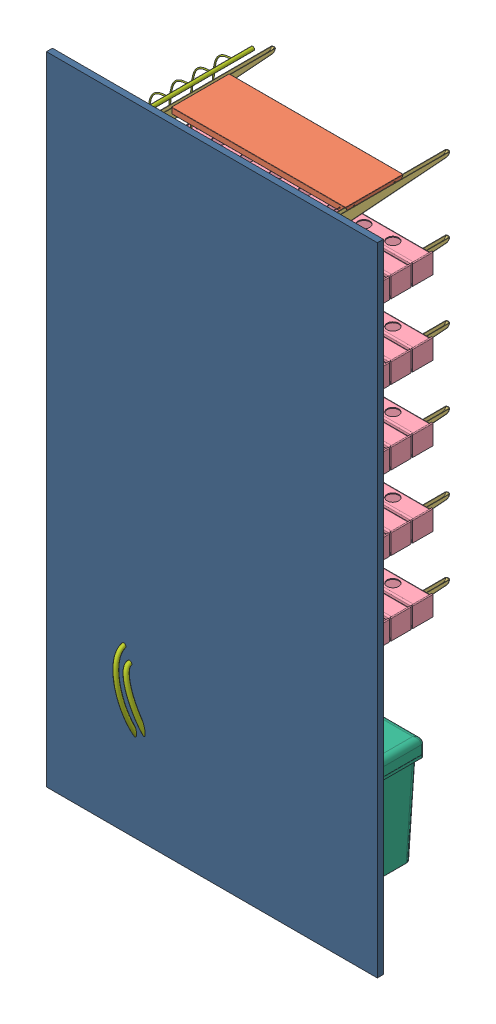
SolidWorks assembly C-W-600, configuration Default. Lengths in mm.
Overall size (1143.31 2200 556.23).
63 component instances, 12 part files, 175 mates.
Components (placement in the parent):
- TSU-W-1: TSU-W [Default] at (314.023 122.1563 -17.0959) size (25 1984 15)
- TSU-W-2: TSU-W [Default] at (-295.977 122.1563 -25) size (25 1984 15)
- TSS-600-1: TSS-600 [Default] at (9.023 818 -235.0528) size (607 37.13 331.17)
- TSUB-1: TSUB [Default] at (314.023 766.5 -17.0959) x (-1 0 0) z (0 0 -1) size (14.07 50.86 484.03)
- TSUB-2: TSUB [Default] at (-295.977 766.5 -25) x (-1 0 0) z (0 0 -1) size (14.07 50.86 484.03)
- TSUB-3: TSUB [Default] at (-295.977 1022.5 -25) x (-1 0 0) z (0 0 -1) size (14.07 50.86 484.03)
- TSUB-4: TSUB [Default] at (314.023 1022.5 -17.0959) x (-1 0 0) z (0 0 -1) size (14.07 50.86 484.03)
- TSS-600-2: TSS-600 [Default] at (9.023 1074 -235.0528) size (607 37.13 331.17)
- TSUB-5: TSUB [Default] at (-295.977 1534.5 -25) x (-1 0 0) z (0 0 -1) size (14.07 50.86 484.03)
- TSUB-6: TSUB [Default] at (314.023 1534.5 -17.0959) x (-1 0 0) z (0 0 -1) size (14.07 50.86 484.03)
- TSS-600-3: TSS-600 [Default] at (9.023 1586 -235.0528) size (607 37.13 331.17)
- TSUB-7: TSUB [Default] at (-295.977 2046.8153 -25) x (-1 0 0) z (0 0 -1) size (14.07 50.86 484.03)
- TSUB-8: TSUB [Default] at (314.023 2046.8153 -17.0959) x (-1 0 0) z (0 0 -1) size (14.07 50.86 484.03)
- TSS-600-4: TSS-600 [Default] at (9.023 2098.3153 -235.0528) size (607 37.13 331.17)
- TSUB-9: TSUB [Default] at (-295.977 1278.5 -25) x (-1 0 0) z (0 0 -1) size (14.07 50.86 484.03)
- TSUB-10: TSUB [Default] at (314.023 1278.5 -17.0959) x (-1 0 0) z (0 0 -1) size (14.07 50.86 484.03)
- TSS-600-5: TSS-600 [Default] at (9.023 1330 -235.0528) size (607 37.13 331.17)
- TSUB-11: TSUB [Default] at (-295.977 1790.5 -25) x (-1 0 0) z (0 0 -1) size (14.07 50.86 484.03)
- TSUB-12: TSUB [Default] at (314.023 1790.5 -17.0959) x (-1 0 0) z (0 0 -1) size (14.07 50.86 484.03)
- TSS-600-6: TSS-600 [Default] at (9.023 1842 -235.0528) size (607 37.13 331.17)
- GB-600-b-1: GB-600-b [Default] at (0 1106.5 -233.7344) size (806 70 70)
- GB-600-p-1: GB-600-p [Default] at (0 1106.5 -233.7344) size (92 218.31 4)
- GB-600-p-2: GB-600-p [Default] at (0 1106.5 -308.7344) size (92 218.31 4)
- GB-600-b-2: GB-600-b [Default] at (0 1106.5 -308.7344) size (806 70 70)
- GB-600-p-3: GB-600-p [Default] at (0 1106.5 -83.7344) size (92 218.31 4)
- GB-600-b-3: GB-600-b [Default] at (0 1106.5 -83.7344) size (806 70 70)
- GB-600-p-4: GB-600-p [Default] at (0 1106.5 -158.7344) size (92 218.31 4)
- GB-600-b-4: GB-600-b [Default] at (0 1106.5 -158.7344) size (806 70 70)
- GB-600-b-5: GB-600-b [Default] at (0 850.5 -83.7344) size (806 70 70)
- GB-600-b-6: GB-600-b [Default] at (0 850.5 -158.7344) size (806 70 70)
- GB-600-b-7: GB-600-b [Default] at (0 850.5 -233.7344) size (806 70 70)
- GB-600-b-8: GB-600-b [Default] at (0 850.5 -308.7344) size (806 70 70)
- GB-600-b-9: GB-600-b [Default] at (0 1618.5 -83.7344) size (806 70 70)
- GB-600-b-10: GB-600-b [Default] at (0 1618.5 -158.7344) size (806 70 70)
- GB-600-b-11: GB-600-b [Default] at (0 1618.5 -233.7344) size (806 70 70)
- GB-600-b-12: GB-600-b [Default] at (0 1618.5 -308.7344) size (806 70 70)
- GB-600-p-5: GB-600-p [Default] at (0 1618.5 -83.7344) size (92 218.31 4)
- GB-600-p-6: GB-600-p [Default] at (0 1618.5 -158.7344) size (92 218.31 4)
- GB-600-p-7: GB-600-p [Default] at (0 1618.5 -233.7344) size (92 218.31 4)
- GB-600-p-8: GB-600-p [Default] at (0 1618.5 -308.7344) size (92 218.31 4)
- GB-600-p-9: GB-600-p [Default] at (0 1362.5 -308.7344) size (92 218.31 4)
- GB-600-p-10: GB-600-p [Default] at (0 1362.5 -233.7344) size (92 218.31 4)
- GB-600-p-11: GB-600-p [Default] at (0 1362.5 -158.7344) size (92 218.31 4)
- GB-600-p-12: GB-600-p [Default] at (0 1362.5 -83.7344) size (92 218.31 4)
- GB-600-b-13: GB-600-b [Default] at (0 1362.5 -308.7344) size (806 70 70)
- GB-600-b-14: GB-600-b [Default] at (0 1362.5 -233.7344) size (806 70 70)
- GB-600-b-15: GB-600-b [Default] at (0 1362.5 -158.7344) size (806 70 70)
- GB-600-b-16: GB-600-b [Default] at (0 1362.5 -83.7344) size (806 70 70)
- GB-600-p-13: GB-600-p [Default] at (0 1874.5 -308.7344) size (92 218.31 4)
- GB-600-p-14: GB-600-p [Default] at (0 1874.5 -233.7344) size (92 218.31 4)
- GB-600-p-15: GB-600-p [Default] at (0 1874.5 -158.7344) size (92 218.31 4)
- GB-600-p-16: GB-600-p [Default] at (0 1874.5 -83.7344) size (92 218.31 4)
- GB-600-b-17: GB-600-b [Default] at (0 1874.5 -83.7344) size (806 70 70)
- GB-600-b-18: GB-600-b [Default] at (0 1874.5 -158.7344) size (806 70 70)
- GB-600-b-19: GB-600-b [Default] at (0 1874.5 -233.7344) size (806 70 70)
- GB-600-b-20: GB-600-b [Default] at (0 1874.5 -308.7344) size (806 70 70)
- WT-1: WT [Default] at (0 320 -217.0959) size (600 370 400)
- Plumbing-1: Plumbing [Default] at (-304.2307 113.1409 -27.6539) size (241.4 2067.5 489.85)
- Wire-1: Wire [Default] at (9.023 2061.1845 -235.0528) x (-1 0 0) z (0 -1 0) size (2 2 1357)
- CCD-1: CCD [Default] at (314.023 122.1563 -17.0959) x (0 0 -1) z (1 0 0) size (82.56 307.09 97.63) (hidden)
- Pump-1: Pump [Default] at (0 5 -217.0959) x (1 0 0) z (0 1 0) size (624.24 196.22 364.08) (hidden)
- power brick-1: power brick [Default] at (321.5508 116.8455 -47.8298) x (0 0 -1) z (1 0 0) size (82.62 120 30)
- Part1^C-W-600-1: Part1^C-W-600 [Default] at (0 0 -217.0959) x (-1 0 0) z (0 -1 0) size (1143.31 20.98 2200) (virtual)
Mates (geometry in assembly coordinates):
- Coincident41: coincident anti-aligned: plane of TSU-W-1 through (307.023 730.1563 -2.0959) normal (1 0 0); plane of TSUB-1 through (307.023 766.5 -17.0959) normal (-1 0 0)
- Coincident42: coincident anti-aligned: plane of TSU-W-1 through (314.023 2106.1563 -17.0959) normal (0 0 -1); plane of TSUB-1 through (321.023 766.5 -17.0959) normal (0 0 1)
- Parallel8: parallel: line of TSU-W-1 through (309 342 -23.5) axis (0 0 -1); plane of TSUB-1 through (299.4677 816.5 -17.0959) normal (0 1 0)
- Coincident44: coincident anti-aligned: plane of TSS-600-1 through (308.523 798 -235.0528) normal (-1 0 0); plane of TSUB-1 through (308.523 766.5 -17.0959) normal (1 0 0)
- Coincident45: coincident anti-aligned: plane of TSS-600-1 through (310.023 816.5 -136.5528) normal (0 -1 0); plane of TSUB-1 through (307.023 816.5 -17.0959) normal (0 1 0)
- Coincident46: coincident anti-aligned: plane of TSU-W-2 through (-302.977 762.1563 -10) normal (1 0 0); plane of TSUB-2 through (-302.977 766.5 -25) normal (-1 0 0)
- Coincident47: coincident anti-aligned: plane of TSU-W-2 through (-295.977 2106.1563 -25) normal (0 0 -1); plane of TSUB-2 through (-302.977 766.5 -25) normal (0 0 1)
- Coincident48: coincident anti-aligned: plane of TSS-600-1 through (310.023 816.5 -136.5528) normal (0 -1 0); plane of TSUB-2 through (-302.977 816.5 -25) normal (0 1 0)
- Coincident49: coincident anti-aligned: plane of TSU-W-1 through (321.023 1018.1563 -2.0959) normal (-1 0 0); plane of TSUB-4 through (321.023 1022.5 -17.0959) normal (1 0 0)
- Coincident50: coincident anti-aligned: plane of TSU-W-1 through (314.023 2106.1563 -17.0959) normal (0 0 -1); plane of TSUB-4 through (321.023 1022.5 -17.0959) normal (0 0 1)
- Coincident51: coincident anti-aligned: plane of TSU-W-2 through (-288.977 1018.1563 -10) normal (-1 0 0); plane of TSUB-3 through (-288.977 1022.5 -25) normal (1 0 0)
- Coincident52: coincident anti-aligned: plane of TSU-W-2 through (-295.977 2106.1563 -25) normal (0 0 -1); plane of TSUB-3 through (-302.977 1022.5 -25) normal (0 0 1)
- Coincident53: coincident anti-aligned: plane of TSUB-4 through (307.023 1072.5 -17.0959) normal (0 1 0); plane of TSS-600-2 through (310.023 1072.5 -136.5528) normal (0 -1 0)
- Coincident54: coincident anti-aligned: plane of TSUB-3 through (-302.977 1072.5 -25) normal (0 1 0); plane of TSS-600-2 through (310.023 1072.5 -136.5528) normal (0 -1 0)
- Coincident55: coincident anti-aligned: plane of TSUB-4 through (308.523 1022.5 -17.0959) normal (1 0 0); plane of TSS-600-2 through (308.523 1054 -235.0528) normal (-1 0 0)
- Coincident56: coincident anti-aligned: plane of TSUB-6 through (308.523 1534.5 -17.0959) normal (1 0 0); plane of TSS-600-3 through (308.523 1566 -235.0528) normal (-1 0 0)
- Coincident57: coincident anti-aligned: plane of TSUB-6 through (307.023 1584.5 -17.0959) normal (0 1 0); plane of TSS-600-3 through (310.023 1584.5 -136.5528) normal (0 -1 0)
- Coincident58: coincident anti-aligned: plane of TSUB-5 through (-302.977 1584.5 -25) normal (0 1 0); plane of TSS-600-3 through (310.023 1584.5 -136.5528) normal (0 -1 0)
- Coincident59: coincident anti-aligned: plane of TSUB-8 through (308.523 2046.8153 -17.0959) normal (1 0 0); plane of TSS-600-4 through (308.523 2078.3153 -235.0528) normal (-1 0 0)
- Coincident60: coincident anti-aligned: plane of TSUB-8 through (307.023 2096.8153 -17.0959) normal (0 1 0); plane of TSS-600-4 through (310.023 2096.8153 -136.5528) normal (0 -1 0)
- Coincident61: coincident anti-aligned: plane of TSUB-7 through (-302.977 2096.8153 -25) normal (0 1 0); plane of TSS-600-4 through (310.023 2096.8153 -136.5528) normal (0 -1 0)
- Coincident62: coincident anti-aligned: plane of TSUB-10 through (308.523 1278.5 -17.0959) normal (1 0 0); plane of TSS-600-5 through (308.523 1310 -235.0528) normal (-1 0 0)
- Coincident63: coincident anti-aligned: plane of TSUB-10 through (307.023 1328.5 -17.0959) normal (0 1 0); plane of TSS-600-5 through (310.023 1328.5 -136.5528) normal (0 -1 0)
- Coincident64: coincident anti-aligned: plane of TSUB-9 through (-302.977 1328.5 -25) normal (0 1 0); plane of TSS-600-5 through (310.023 1328.5 -136.5528) normal (0 -1 0)
- Coincident65: coincident anti-aligned: plane of TSUB-12 through (308.523 1790.5 -17.0959) normal (1 0 0); plane of TSS-600-6 through (308.523 1822 -235.0528) normal (-1 0 0)
- Coincident66: coincident anti-aligned: plane of TSUB-12 through (307.023 1840.5 -17.0959) normal (0 1 0); plane of TSS-600-6 through (310.023 1840.5 -136.5528) normal (0 -1 0)
- Coincident67: coincident anti-aligned: plane of TSUB-11 through (-302.977 1840.5 -25) normal (0 1 0); plane of TSS-600-6 through (310.023 1840.5 -136.5528) normal (0 -1 0)
- Coincident70: coincident anti-aligned: plane of TSU-W-1 through (314.023 2106.1563 -17.0959) normal (0 0 -1); plane of TSUB-10 through (307.023 1278.5 -17.0959) normal (0 0 1)
- Coincident71: coincident anti-aligned: plane of TSU-W-2 through (-295.977 2106.1563 -25) normal (0 0 -1); plane of TSUB-9 through (-302.977 1278.5 -25) normal (0 0 1)
- Coincident72: coincident aligned: plane of TSUB-3 through (-288.977 1022.5 -25) normal (1 0 0); plane of TSUB-9 through (-288.977 1278.5 -25) normal (1 0 0)
- Coincident73: coincident aligned: plane of TSUB-4 through (307.023 1022.5 -17.0959) normal (-1 0 0); plane of TSUB-10 through (307.023 1278.5 -17.0959) normal (-1 0 0)
- Coincident74: coincident anti-aligned: plane of TSU-W-1 through (314.023 2106.1563 -17.0959) normal (0 0 -1); plane of TSUB-6 through (307.023 1534.5 -17.0959) normal (0 0 1)
- Coincident75: coincident anti-aligned: plane of TSU-W-2 through (-295.977 2106.1563 -25) normal (0 0 -1); plane of TSUB-5 through (-302.977 1534.5 -25) normal (0 0 1)
- Coincident76: coincident aligned: plane of TSUB-5 through (-288.977 1534.5 -25) normal (1 0 0); plane of TSUB-9 through (-288.977 1278.5 -25) normal (1 0 0)
- Coincident78: coincident aligned: plane of TSUB-6 through (321.023 1534.5 -17.0959) normal (1 0 0); plane of TSUB-12 through (321.023 1790.5 -17.0959) normal (1 0 0)
- Coincident79: coincident aligned: plane of TSUB-6 through (307.023 1534.5 -17.0959) normal (-1 0 0); plane of TSUB-10 through (307.023 1278.5 -17.0959) normal (-1 0 0)
- Coincident80: coincident anti-aligned: plane of TSU-W-1 through (314.023 2106.1563 -17.0959) normal (0 0 -1); plane of TSUB-12 through (307.023 1790.5 -17.0959) normal (0 0 1)
- Coincident81: coincident anti-aligned: plane of TSU-W-2 through (-302.977 1786.1563 -10) normal (1 0 0); plane of TSUB-11 through (-302.977 1790.5 -25) normal (-1 0 0)
- Coincident82: coincident anti-aligned: plane of TSU-W-2 through (-295.977 2106.1563 -25) normal (0 0 -1); plane of TSUB-11 through (-302.977 1790.5 -25) normal (0 0 1)
- Coincident83: coincident anti-aligned: plane of TSU-W-2 through (-302.977 2042.1563 -10) normal (1 0 0); plane of TSUB-7 through (-302.977 2046.8153 -25) normal (-1 0 0)
- Coincident84: coincident anti-aligned: plane of TSU-W-2 through (-295.977 2106.1563 -25) normal (0 0 -1); plane of TSUB-7 through (-302.977 2046.8153 -25) normal (0 0 1)
- Coincident85: coincident anti-aligned: plane of TSU-W-1 through (307.023 2074.1563 -2.0959) normal (1 0 0); plane of TSUB-8 through (307.023 2046.8153 -17.0959) normal (-1 0 0)
- Coincident86: coincident anti-aligned: plane of TSU-W-1 through (314.023 2106.1563 -17.0959) normal (0 0 -1); plane of TSUB-8 through (307.023 2046.8153 -17.0959) normal (0 0 1)
- Coincident89: coincident: line of TSU-W-1 through (309 2070 -23.5) axis (0 0 -1); plane of TSUB-8 through (334.728 2070 -17.0959) normal (0 1 0)
- Coincident90: coincident aligned: plane of TSS-600-4 through (310.023 2098.3153 -335.0528) normal (0 0 -1); plane of TSS-600-6 through (310.023 1842 -335.0528) normal (0 0 -1)
- Coincident91: coincident aligned: plane of TSS-600-3 through (310.023 1586 -335.0528) normal (0 0 -1); plane of TSS-600-6 through (310.023 1842 -335.0528) normal (0 0 -1)
- Coincident93: coincident aligned: plane of TSS-600-3 through (310.023 1586 -335.0528) normal (0 0 -1); plane of TSS-600-5 through (310.023 1330 -335.0528) normal (0 0 -1)
- Coincident94: coincident aligned: plane of TSS-600-2 through (310.023 1074 -335.0528) normal (0 0 -1); plane of TSS-600-5 through (310.023 1330 -335.0528) normal (0 0 -1)
- Coincident95: coincident aligned: plane of TSS-600-1 through (310.023 818 -335.0528) normal (0 0 -1); plane of TSS-600-2 through (310.023 1074 -335.0528) normal (0 0 -1)
- Coincident153: coincident: line of TSU-F-L-P-1 through (312 1814 -23.5) axis (0 0 -1); plane of TSUB-12 through (333.2603 1814 -25) normal (0 1 0)
- Coincident155: coincident: line of TSU-F-L-P-1 through (312 1558 -23.5) axis (0 0 -1); plane of TSUB-6 through (333.2603 1558 -25) normal (0 1 0)
- Coincident157: coincident: line of TSU-F-L-P-1 through (312 1302 -23.5) axis (0 0 -1); plane of TSUB-10 through (333.2603 1302 -25) normal (0 1 0)
- Coincident159: coincident: line of TSU-F-L-P-1 through (312 1046 -23.5) axis (0 0 -1); plane of TSUB-4 through (333.2603 1046 -25) normal (0 1 0)
- Coincident167: coincident: line of TSU-F-L-P-1 through (312 790 -23.5) axis (0 0 -1); plane of TSUB-1 through (333.2603 790 -25) normal (0 1 0)
- Concentric31: concentric aligned: cylinder of GB-600-b-1 through (-375 1071.5 -233.7344) axis (0 1 0) radius 2; cylinder of GB-600-p-1 through (-375 877 -233.7344) axis (0 1 0) radius 2
- Distance1: distance = 10 mm aligned: plane of GB-600-p-1 through (-375 1087 -233.7344) normal (0 1 0); plane of GB-600-b-1 through (400 1077 -201.2344) normal (0 1 0)
- Parallel10: parallel anti-aligned: plane of TSU-W-1 through (314.023 2106.1563 -17.0959) normal (0 0 -1); plane of GB-600-b-1 through (400 1074 -201.2344) normal (0 0 1)
- Coincident201: coincident aligned: plane of GB-600-b-1 through (0 1106.5 -233.7344) normal (1 0 0)
- Coincident202: coincident anti-aligned: plane of TSS-600-2 through (310.023 1074 -135.0528) normal (0 1 0); plane of GB-600-b-1 through (400 1074 -201.2344) normal (0 -1 0)
- Concentric32: concentric aligned: cylinder of GB-600-p-2 through (-375 877 -308.7344) axis (0 1 0) radius 2; cylinder of GB-600-b-2 through (-375 1071.5 -308.7344) axis (0 1 0) radius 2
- Distance2: distance = 10 mm aligned: plane of GB-600-p-2 through (-375 1087 -308.7344) normal (0 1 0); plane of GB-600-b-2 through (400 1077 -276.2344) normal (0 1 0)
- Concentric33: concentric aligned: cylinder of GB-600-p-3 through (-375 877 -83.7344) axis (0 1 0) radius 2; cylinder of GB-600-b-3 through (-375 1071.5 -83.7344) axis (0 1 0) radius 2
- Distance3: distance = 10 mm aligned: plane of GB-600-p-3 through (-375 1087 -83.7344) normal (0 1 0); plane of GB-600-b-3 through (400 1077 -51.2344) normal (0 1 0)
- Concentric34: concentric aligned: cylinder of GB-600-p-4 through (-375 877 -158.7344) axis (0 1 0) radius 2; cylinder of GB-600-b-4 through (-375 1071.5 -158.7344) axis (0 1 0) radius 2
- Distance4: distance = 10 mm aligned: plane of GB-600-p-4 through (-375 1087 -158.7344) normal (0 1 0); plane of GB-600-b-4 through (400 1077 -126.2344) normal (0 1 0)
- Coincident203: coincident anti-aligned: plane of TSS-600-2 through (310.023 1074 -135.0528) normal (0 1 0); plane of GB-600-b-2 through (400 1074 -276.2344) normal (0 -1 0)
- Coincident204: coincident anti-aligned: plane of TSS-600-2 through (310.023 1074 -135.0528) normal (0 1 0); plane of GB-600-b-4 through (400 1074 -126.2344) normal (0 -1 0)
- Coincident205: coincident anti-aligned: plane of TSS-600-2 through (310.023 1074 -135.0528) normal (0 1 0); plane of GB-600-b-3 through (400 1074 -51.2344) normal (0 -1 0)
- Coincident206: coincident aligned: plane of GB-600-b-1 through (403 1106.5 -233.7344) normal (1 0 0); plane of GB-600-b-4 through (403 1106.5 -158.7344) normal (1 0 0)
- Coincident207: coincident aligned: plane of GB-600-b-3 through (403 1106.5 -83.7344) normal (1 0 0); plane of GB-600-b-4 through (403 1106.5 -158.7344) normal (1 0 0)
- Coincident208: coincident aligned: plane of GB-600-b-1 through (403 1106.5 -233.7344) normal (1 0 0); plane of GB-600-b-2 through (403 1106.5 -308.7344) normal (1 0 0)
- Distance5: distance = 10 mm anti-aligned: plane of GB-600-b-4 through (400 1074 -191.2344) normal (0 0 -1); plane of GB-600-b-1 through (400 1074 -201.2344) normal (0 0 1)
- Distance6: distance = 10 mm anti-aligned: plane of GB-600-b-4 through (400 1074 -126.2344) normal (0 0 1); plane of GB-600-b-3 through (400 1074 -116.2344) normal (0 0 -1)
- Distance7: distance = 10 mm anti-aligned: plane of GB-600-b-1 through (400 1074 -266.2344) normal (0 0 -1); plane of GB-600-b-2 through (400 1074 -276.2344) normal (0 0 1)
- Distance8: distance = 10 mm anti-aligned: plane of GB-600-b-6 through (400 818 -126.2344) normal (0 0 1); plane of GB-600-b-5 through (400 818 -116.2344) normal (0 0 -1)
- Distance9: distance = 10 mm anti-aligned: plane of GB-600-b-6 through (400 818 -191.2344) normal (0 0 -1); plane of GB-600-b-7 through (400 818 -201.2344) normal (0 0 1)
- Coincident212: coincident aligned: plane of GB-600-b-5 through (403 850.5 -83.7344) normal (1 0 0); plane of GB-600-b-6 through (403 850.5 -158.7344) normal (1 0 0)
- Coincident213: coincident aligned: plane of GB-600-b-7 through (403 850.5 -233.7344) normal (1 0 0); plane of GB-600-b-8 through (403 850.5 -308.7344) normal (1 0 0)
- Coincident214: coincident aligned: plane of GB-600-b-6 through (403 850.5 -158.7344) normal (1 0 0); plane of GB-600-b-7 through (403 850.5 -233.7344) normal (1 0 0)
- Distance10: distance = 10 mm anti-aligned: plane of GB-600-b-7 through (400 818 -266.2344) normal (0 0 -1); plane of GB-600-b-8 through (400 818 -276.2344) normal (0 0 1)
- Coincident215: coincident aligned: plane of GB-600-b-7 through (400 818 -201.2344) normal (0 -1 0); plane of GB-600-b-8 through (400 818 -276.2344) normal (0 -1 0)
- Coincident216: coincident aligned: plane of GB-600-b-6 through (400 818 -126.2344) normal (0 -1 0); plane of GB-600-b-7 through (400 818 -201.2344) normal (0 -1 0)
- Coincident217: coincident aligned: plane of GB-600-b-5 through (400 818 -51.2344) normal (0 -1 0); plane of GB-600-b-6 through (400 818 -126.2344) normal (0 -1 0)
- Coincident218: coincident anti-aligned: plane of TSS-600-1 through (310.023 818 -135.0528) normal (0 1 0); plane of GB-600-b-7 through (400 818 -201.2344) normal (0 -1 0)
- Concentric35: concentric aligned: cylinder of GB-600-p-2 through (-375 877 -308.7344) axis (0 1 0) radius 2; cylinder of GB-600-b-8 through (-375 815.499 -308.7344) axis (0 1 0) radius 4
- Concentric36: concentric aligned: cylinder of GB-600-b-9 through (-375 1583.5 -83.7344) axis (0 1 0) radius 2; cylinder of GB-600-p-5 through (-375 1389 -83.7344) axis (0 1 0) radius 2
- Distance11: distance = 10 mm anti-aligned: plane of GB-600-b-10 through (400 1586 -126.2344) normal (0 0 1); plane of GB-600-b-9 through (400 1586 -116.2344) normal (0 0 -1)
- Concentric37: concentric aligned: cylinder of GB-600-b-12 through (-375 1583.5 -308.7344) axis (0 1 0) radius 2; cylinder of GB-600-p-8 through (-375 1389 -308.7344) axis (0 1 0) radius 2
- Concentric38: concentric aligned: cylinder of GB-600-b-11 through (-375 1583.5 -233.7344) axis (0 1 0) radius 2; cylinder of GB-600-p-7 through (-375 1389 -233.7344) axis (0 1 0) radius 2
- Distance12: distance = 10 mm aligned: plane of GB-600-p-7 through (-375 1599 -233.7344) normal (0 1 0); plane of GB-600-b-11 through (400 1589 -201.2344) normal (0 1 0)
- Distance13: distance = 10 mm anti-aligned: plane of GB-600-b-10 through (400 1586 -191.2344) normal (0 0 -1); plane of GB-600-b-11 through (400 1586 -201.2344) normal (0 0 1)
- Concentric39: concentric aligned: cylinder of GB-600-b-10 through (-375 1583.5 -158.7344) axis (0 1 0) radius 2; cylinder of GB-600-p-6 through (-375 1389 -158.7344) axis (0 1 0) radius 2
- Distance14: distance = 10 mm aligned: plane of GB-600-p-8 through (-375 1599 -308.7344) normal (0 1 0); plane of GB-600-b-12 through (400 1589 -276.2344) normal (0 1 0)
- Distance15: distance = 10 mm aligned: plane of GB-600-p-5 through (-375 1599 -83.7344) normal (0 1 0); plane of GB-600-b-9 through (400 1589 -51.2344) normal (0 1 0)
- Distance16: distance = 10 mm aligned: plane of GB-600-p-6 through (-375 1599 -158.7344) normal (0 1 0); plane of GB-600-b-10 through (400 1589 -126.2344) normal (0 1 0)
- Coincident220: coincident aligned: plane of GB-600-b-9 through (403 1618.5 -83.7344) normal (1 0 0); plane of GB-600-b-10 through (403 1618.5 -158.7344) normal (1 0 0)
- Coincident221: coincident aligned: plane of GB-600-b-11 through (403 1618.5 -233.7344) normal (1 0 0); plane of GB-600-b-12 through (403 1618.5 -308.7344) normal (1 0 0)
- Coincident222: coincident aligned: plane of GB-600-b-10 through (403 1618.5 -158.7344) normal (1 0 0); plane of GB-600-b-11 through (403 1618.5 -233.7344) normal (1 0 0)
- Distance17: distance = 10 mm anti-aligned: plane of GB-600-b-11 through (400 1586 -266.2344) normal (0 0 -1); plane of GB-600-b-12 through (400 1586 -276.2344) normal (0 0 1)
- Coincident223: coincident aligned: plane of GB-600-b-12 through (400 1586 -276.2344) normal (0 -1 0); plane of GB-600-b-9 through (400 1586 -51.2344) normal (0 -1 0)
- Coincident224: coincident aligned: plane of GB-600-b-9 through (400 1586 -51.2344) normal (0 -1 0); plane of GB-600-b-10 through (400 1586 -126.2344) normal (0 -1 0)
- Coincident225: coincident aligned: plane of GB-600-b-10 through (400 1586 -126.2344) normal (0 -1 0); plane of GB-600-b-11 through (400 1586 -201.2344) normal (0 -1 0)
- Coincident226: coincident aligned: plane of GB-600-b-15 through (400 1330 -126.2344) normal (0 -1 0); plane of GB-600-b-16 through (400 1330 -51.2344) normal (0 -1 0)
- Coincident227: coincident aligned: plane of GB-600-b-14 through (400 1330 -201.2344) normal (0 -1 0); plane of GB-600-b-15 through (400 1330 -126.2344) normal (0 -1 0)
- Coincident228: coincident aligned: plane of GB-600-b-14 through (403 1362.5 -233.7344) normal (1 0 0); plane of GB-600-b-15 through (403 1362.5 -158.7344) normal (1 0 0)
- Distance18: distance = 10 mm anti-aligned: plane of GB-600-b-14 through (400 1330 -266.2344) normal (0 0 -1); plane of GB-600-b-13 through (400 1330 -276.2344) normal (0 0 1)
- Coincident229: coincident aligned: plane of GB-600-b-13 through (400 1330 -276.2344) normal (0 -1 0); plane of GB-600-b-16 through (400 1330 -51.2344) normal (0 -1 0)
- Concentric40: concentric aligned: cylinder of GB-600-p-10 through (-375 1133 -233.7344) axis (0 1 0) radius 2; cylinder of GB-600-b-14 through (-375 1327.5 -233.7344) axis (0 1 0) radius 2
- Distance19: distance = 10 mm aligned: plane of GB-600-p-11 through (-375 1343 -158.7344) normal (0 1 0); plane of GB-600-b-15 through (400 1333 -126.2344) normal (0 1 0)
- Concentric41: concentric aligned: cylinder of GB-600-p-12 through (-375 1133 -83.7344) axis (0 1 0) radius 2; cylinder of GB-600-b-16 through (-375 1327.5 -83.7344) axis (0 1 0) radius 2
- Distance20: distance = 10 mm aligned: plane of GB-600-p-12 through (-375 1343 -83.7344) normal (0 1 0); plane of GB-600-b-16 through (400 1333 -51.2344) normal (0 1 0)
- Distance21: distance = 10 mm anti-aligned: plane of GB-600-b-15 through (400 1330 -126.2344) normal (0 0 1); plane of GB-600-b-16 through (400 1330 -116.2344) normal (0 0 -1)
- Coincident230: coincident aligned: plane of GB-600-b-15 through (403 1362.5 -158.7344) normal (1 0 0); plane of GB-600-b-16 through (403 1362.5 -83.7344) normal (1 0 0)
- Distance22: distance = 10 mm anti-aligned: plane of GB-600-b-15 through (400 1330 -191.2344) normal (0 0 -1); plane of GB-600-b-14 through (400 1330 -201.2344) normal (0 0 1)
- Concentric42: concentric aligned: cylinder of GB-600-p-9 through (-375 1133 -308.7344) axis (0 1 0) radius 2; cylinder of GB-600-b-13 through (-375 1327.5 -308.7344) axis (0 1 0) radius 2
- Distance23: distance = 10 mm aligned: plane of GB-600-p-9 through (-375 1343 -308.7344) normal (0 1 0); plane of GB-600-b-13 through (400 1333 -276.2344) normal (0 1 0)
- Distance24: distance = 10 mm aligned: plane of GB-600-p-10 through (-375 1343 -233.7344) normal (0 1 0); plane of GB-600-b-14 through (400 1333 -201.2344) normal (0 1 0)
- Concentric43: concentric aligned: cylinder of GB-600-p-11 through (-375 1133 -158.7344) axis (0 1 0) radius 2; cylinder of GB-600-b-15 through (-375 1327.5 -158.7344) axis (0 1 0) radius 2
- Coincident231: coincident aligned: plane of GB-600-b-13 through (403 1362.5 -308.7344) normal (1 0 0); plane of GB-600-b-14 through (403 1362.5 -233.7344) normal (1 0 0)
- Coincident232: coincident anti-aligned: plane of TSS-600-5 through (310.023 1330 -135.0528) normal (0 1 0); plane of GB-600-b-13 through (400 1330 -276.2344) normal (0 -1 0)
- Coincident233: coincident aligned: plane of GB-600-b-2 through (400 1074 -341.2344) normal (0 0 -1); plane of GB-600-b-13 through (400 1330 -341.2344) normal (0 0 -1)
- Coincident234: coincident aligned: plane of GB-600-b-2 through (403 1106.5 -308.7344) normal (1 0 0); plane of GB-600-b-13 through (403 1362.5 -308.7344) normal (1 0 0)
- Coincident235: coincident anti-aligned: plane of TSS-600-3 through (310.023 1586 -135.0528) normal (0 1 0); plane of GB-600-b-12 through (400 1586 -276.2344) normal (0 -1 0)
- Coincident236: coincident aligned: plane of GB-600-b-12 through (-403 1618.5 -308.7344) normal (-1 0 0); plane of GB-600-b-13 through (-403 1362.5 -308.7344) normal (-1 0 0)
- Coincident237: coincident aligned: plane of GB-600-b-12 through (400 1586 -341.2344) normal (0 0 -1); plane of GB-600-b-13 through (400 1330 -341.2344) normal (0 0 -1)
- Coincident238: coincident aligned: plane of GB-600-b-17 through (400 1842 -51.2344) normal (0 -1 0); plane of GB-600-b-18 through (400 1842 -126.2344) normal (0 -1 0)
- Coincident239: coincident aligned: plane of GB-600-b-18 through (400 1842 -126.2344) normal (0 -1 0); plane of GB-600-b-19 through (400 1842 -201.2344) normal (0 -1 0)
- Coincident240: coincident aligned: plane of GB-600-b-18 through (403 1874.5 -158.7344) normal (1 0 0); plane of GB-600-b-19 through (403 1874.5 -233.7344) normal (1 0 0)
- Distance25: distance = 10 mm anti-aligned: plane of GB-600-b-19 through (400 1842 -266.2344) normal (0 0 -1); plane of GB-600-b-20 through (400 1842 -276.2344) normal (0 0 1)
- Coincident241: coincident aligned: plane of GB-600-b-17 through (400 1842 -51.2344) normal (0 -1 0); plane of GB-600-b-20 through (400 1842 -276.2344) normal (0 -1 0)
- Concentric44: concentric aligned: cylinder of GB-600-p-14 through (-375 1645 -233.7344) axis (0 1 0) radius 2; cylinder of GB-600-b-19 through (-375 1839.5 -233.7344) axis (0 1 0) radius 2
- Distance26: distance = 10 mm aligned: plane of GB-600-p-15 through (-375 1855 -158.7344) normal (0 1 0); plane of GB-600-b-18 through (400 1845 -126.2344) normal (0 1 0)
- Concentric45: concentric aligned: cylinder of GB-600-p-16 through (-375 1645 -83.7344) axis (0 1 0) radius 2; cylinder of GB-600-b-17 through (-375 1839.5 -83.7344) axis (0 1 0) radius 2
- Distance27: distance = 10 mm aligned: plane of GB-600-p-16 through (-375 1855 -83.7344) normal (0 1 0); plane of GB-600-b-17 through (400 1845 -51.2344) normal (0 1 0)
- Distance28: distance = 10 mm anti-aligned: plane of GB-600-b-18 through (400 1842 -126.2344) normal (0 0 1); plane of GB-600-b-17 through (400 1842 -116.2344) normal (0 0 -1)
- Coincident242: coincident aligned: plane of GB-600-b-17 through (403 1874.5 -83.7344) normal (1 0 0); plane of GB-600-b-18 through (403 1874.5 -158.7344) normal (1 0 0)
- Distance29: distance = 10 mm anti-aligned: plane of GB-600-b-18 through (400 1842 -191.2344) normal (0 0 -1); plane of GB-600-b-19 through (400 1842 -201.2344) normal (0 0 1)
- Concentric46: concentric aligned: cylinder of GB-600-p-13 through (-375 1645 -308.7344) axis (0 1 0) radius 2; cylinder of GB-600-b-20 through (-375 1839.5 -308.7344) axis (0 1 0) radius 2
- Distance30: distance = 10 mm aligned: plane of GB-600-p-13 through (-375 1855 -308.7344) normal (0 1 0); plane of GB-600-b-20 through (400 1845 -276.2344) normal (0 1 0)
- Distance31: distance = 10 mm aligned: plane of GB-600-p-14 through (-375 1855 -233.7344) normal (0 1 0); plane of GB-600-b-19 through (400 1845 -201.2344) normal (0 1 0)
- Concentric47: concentric aligned: cylinder of GB-600-p-15 through (-375 1645 -158.7344) axis (0 1 0) radius 2; cylinder of GB-600-b-18 through (-375 1839.5 -158.7344) axis (0 1 0) radius 2
- Coincident243: coincident aligned: plane of GB-600-b-19 through (403 1874.5 -233.7344) normal (1 0 0); plane of GB-600-b-20 through (403 1874.5 -308.7344) normal (1 0 0)
- Coincident244: coincident anti-aligned: plane of TSS-600-6 through (310.023 1842 -135.0528) normal (0 1 0); plane of GB-600-b-20 through (400 1842 -276.2344) normal (0 -1 0)
- Coincident245: coincident aligned: plane of GB-600-b-12 through (400 1586 -341.2344) normal (0 0 -1); plane of GB-600-b-20 through (400 1842 -341.2344) normal (0 0 -1)
- Coincident246: coincident aligned: plane of GB-600-b-12 through (-403 1618.5 -308.7344) normal (-1 0 0); plane of GB-600-b-20 through (-403 1874.5 -308.7344) normal (-1 0 0)
- Coincident247: coincident anti-aligned: plane of Part3-1 through (0 0 -217.0959) normal (0 -1 0)
- Coincident248: coincident aligned: plane of Part3-1 through (0 320 -217.0959) normal (1 0 0)
- Coincident249: coincident anti-aligned: plane of TSU-W-1 through (314.023 2106.1563 -17.0959) normal (0 0 -1); plane of Part3-1 through (0 370 -17.0959) normal (0 0 1)
- Coincident250: coincident aligned: plane of GB-600-b-2 through (403 1106.5 -308.7344) normal (1 0 0); plane of GB-600-b-8 through (403 850.5 -308.7344) normal (1 0 0)
- InPlace1: in place: plane of ? through (-305 2113.5 25) normal (0 0 1); plane of ? through (0 0 25) normal (0 0 1); moOrthogonalPlaneRef_w of ? through (-305 2113.5 25) normal (0 0 1); plane of ? through (0 0 25) normal (0 1 0); plane of ? through (-305 2113.5 25) normal (0 0 1); plane of ? through (0 0 25) normal (1 0 0); plane of ? through (-305 2113.5 25) normal (0 0 1); unknown of ?
- Coincident251: coincident aligned: plane of TSU-W-2; plane of Plumbing-1
- Coincident252: coincident aligned: moOrthogonalPlaneRef_w of TSU-F-L-P-2 through (-305 113.5 25) normal (0 1 0); plane of Part5-1 through (-305 113.5 25) normal (0 1 0)
- Coincident253: coincident anti-aligned: moOrthogonalPlaneRef_w of TSU-F-L-P-2 through (-305 113.5 25) normal (-1 0 0); plane of Part5-1 through (-305 113.5 25) normal (1 0 0)
- InPlace2: in place: plane of ? through (0 2060.8692 30.3916) normal (0 -1 0); plane of ? through (0 2060.8692 0) normal (0 -1 0); plane of ? through (0 2060.8692 30.3916) normal (0 -1 0); plane of ? through (0 2060.8692 0) normal (0 0 -1); plane of ? through (0 2060.8692 30.3916) normal (0 -1 0); plane of ? through (0 2060.8692 0) normal (-1 0 0); plane of TSS-600-4 through (9.023 2061.1845 -5.8789) normal (0 -1 0); unknown of Wire-1
- Coincident251: coincident aligned: plane of TSS-600-4; plane of Wire-1
- Coincident252: coincident aligned: moOrthogonalPlaneRef_w of TSS-600-4 through (9.023 2061.1845 -235.0528) normal (0 0 -1); plane of Part1-1 through (9.023 2061.1845 -235.0528) normal (0 0 -1)
- Coincident253: coincident anti-aligned: moOrthogonalPlaneRef_w of TSS-600-4 through (9.023 2061.1845 -235.0528) normal (1 0 0); plane of Part1-1 through (9.023 2061.1845 -235.0528) normal (-1 0 0)
- InPlace3: in place: plane of ? through (305 113.5 -25) normal (1 0 0); plane of ? through (305 113.5 -25) normal (1 0 0); plane of ? through (305 113.5 -25) normal (1 0 0); plane of ? through (305 113.5 -25) normal (0 1 0); plane of ? through (305 113.5 -25) normal (1 0 0); plane of ? through (305 113.5 -25) normal (0 0 -1); plane of TSU-W-1 through (314.023 122.1563 -17.0959) normal (1 0 0); unknown of CCD-1
- Coincident254: coincident aligned: plane of ?; plane of CCD-1
- Coincident255: coincident aligned: moOrthogonalPlaneRef_w of TSU-W-1; plane of Part2-1 through (314.023 122.1563 -17.0959) normal (0 1 0)
- Coincident256: coincident anti-aligned: moOrthogonalPlaneRef_w of TSU-W-1 through (-17.0959 0 0) axis (1 0 0); plane of Part2-1 through (314.023 122.1563 -17.0959) normal (0 0 -1)
- InPlace4: in place: plane of ? through (0 5 -225) normal (0 1 0); plane of ? through (0 5 0) normal (0 1 0); plane of ? through (0 5 -225) normal (0 1 0); plane of ? through (0 5 0) normal (0 0 -1); plane of ? through (0 5 -225) normal (0 1 0); plane of ? through (0 5 0) normal (1 0 0); plane of WT-1 through (0 5 -217.0959) normal (0 1 0); unknown of Pump-1
- Coincident257: coincident aligned: plane of WT-1; plane of Pump-1
- Coincident258: coincident aligned: moOrthogonalPlaneRef_w of Part3-1 through (0 5 -217.0959) normal (0 0 -1); plane of ele-1 through (0 5 -217.0959) normal (0 0 -1)
- Coincident259: coincident anti-aligned: moOrthogonalPlaneRef_w of Part3-1 through (0 5 -217.0959) normal (-1 0 0); plane of ele-1 through (0 5 -217.0959) normal (1 0 0)
- InPlace5: in place: plane of ? through (317.5 2113.5 -22) normal (1 0 0); plane of ? through (317.5 0 0) normal (1 0 0); plane of ? through (317.5 2113.5 -22) normal (1 0 0); plane of ? through (317.5 0 0) normal (0 1 0); plane of ? through (317.5 2113.5 -22) normal (1 0 0); plane of ? through (317.5 0 0) normal (0 0 -1); plane of ? through (317.5 2113.5 -22) normal (1 0 0); unknown of ?
- Coincident260: coincident aligned: plane of ?; plane of power brick-1
- Coincident261: coincident aligned: moOrthogonalPlaneRef_w of TSU-F-L-P-1 through (317.5 113.5 -25) normal (0 1 0); plane of Part4^Assem1-1 through (317.5 113.5 -25) normal (0 1 0)
- Coincident262: coincident anti-aligned: moOrthogonalPlaneRef_w of TSU-F-L-P-1 through (317.5 113.5 -25) normal (0 0 1); plane of Part4^Assem1-1 through (317.5 113.5 -25) normal (0 0 -1)
- Distance32: distance = 585 mm anti-aligned: plane of TSU-W-1 through (301.523 2106.1563 -14.0959) normal (-1 0 0); plane of TSU-W-2 through (-283.477 2106.1563 -22) normal (1 0 0)
- Coincident252: coincident aligned: plane of TSU-W-1 through (323.523 2106.1563 -14.0959) normal (0 1 0); plane of TSU-W-2 through (-286.477 2106.1563 -22) normal (0 1 0)
- InPlace6: in place: plane of WT-1 through (0 0 -217.0959) normal (0 -1 0); plane of ? through (0 0 0) normal (0 -1 0); plane of WT-1 through (0 0 -217.0959) normal (0 -1 0); plane of ? through (0 0 0) normal (0 0 -1); plane of WT-1 through (0 0 -217.0959) normal (0 -1 0); plane of ? through (0 0 0) normal (-1 0 0); plane of WT-1 through (0 0 -217.0959) normal (0 -1 0); unknown of Part1^C-W-600-1
- Coincident253: coincident aligned: plane of WT-1; plane of Part1^C-W-600-1
- Coincident254: coincident aligned: moOrthogonalPlaneRef_w of Part3-1 through (0 0 -217.0959) normal (0 0 -1); plane of Part1^C-W-600-1 through (0 0 -217.0959) normal (0 0 -1)
- Coincident255: coincident anti-aligned: moOrthogonalPlaneRef_w of Part3-1 through (0 0 -217.0959) normal (1 0 0); plane of Part1^C-W-600-1 through (0 0 -217.0959) normal (-1 0 0)
